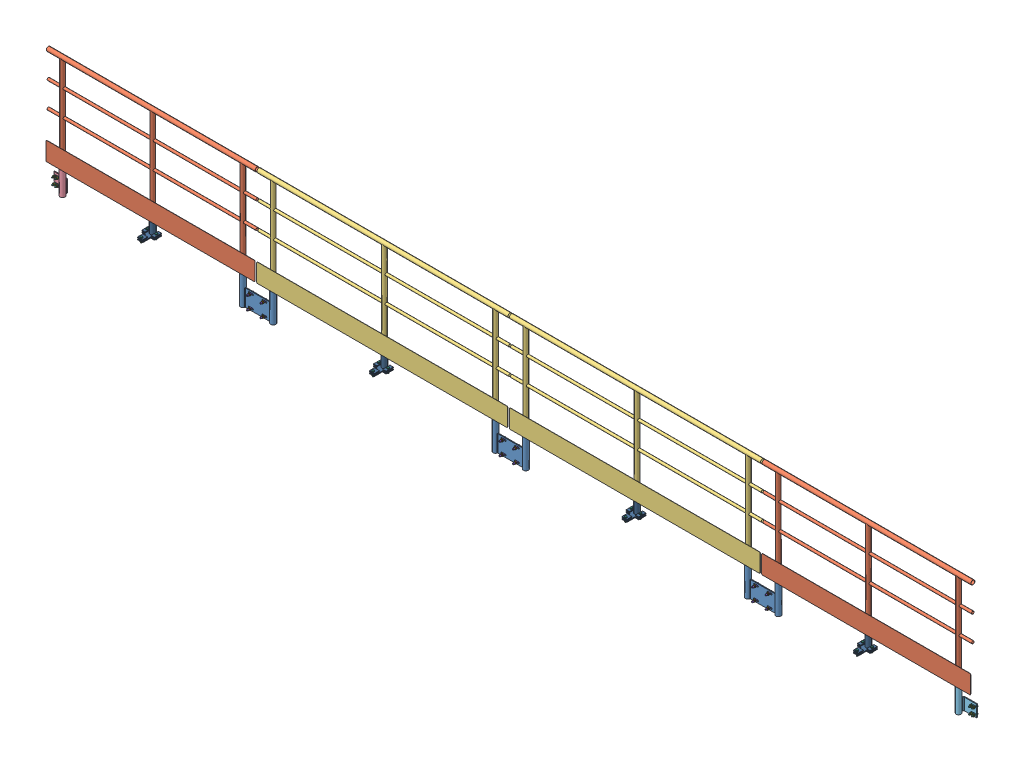
SolidWorks assembly 0402-RAILING ASSEMBLAGE, configuration Predeterminado. Lengths in mm.
Overall size (10980 1510 225).
76 component instances, 10 part files, 77 mates.
Components (placement in the parent):
- 0416-RAILING SUPPORT-1: 0416-RAILING SUPPORT [Predeterminado<Como mecanizada>] at (-587.6244 -491.8214 0) size (420 340 60)
- 0417-RAILING-1: 0417-RAILING [Predeterminado<Como mecanizada>] at (-3078.6244 -351.8214 -5) x (0 0 -1) z (1 0 0) size (53 1270 2480)
- 0420-LONG RAILING-1: 0420-LONG RAILING [Predeterminado<Como mecanizada>] at (-576.6244 -351.8214 -5) x (0 0 -1) z (1 0 0) size (53 1270 2980)
- 0416-RAILING SUPPORT-2: 0416-RAILING SUPPORT [Predeterminado<Como mecanizada>] at (2412.3756 -491.8214 0) size (420 340 60)
- 0416-RAILING SUPPORT-3: 0416-RAILING SUPPORT [Predeterminado<Como mecanizada>] at (5412.3756 -491.8214 0) size (420 340 60)
- 0420-LONG RAILING-2: 0420-LONG RAILING [Predeterminado<Como mecanizada>] at (2423.3756 -351.8214 -5) x (0 0 -1) z (1 0 0) size (53 1270 2980)
- 0417-RAILING-2: 0417-RAILING [Predeterminado<Como mecanizada>] at (5421.3756 -351.8214 -5) x (0 0 -1) z (1 0 0) size (53 1270 2480)
- 0421-RAILING SUPPORT-1: 0421-RAILING SUPPORT [Predeterminado<Como mecanizada>] at (-2909.6244 -531.8214 -5) x (0 0 -1) z (0 -1 0) size (96 190 280)
- 0422-RAILING SUPPORT-1: 0422-RAILING SUPPORT [Predeterminado<Como mecanizada>] at (7732.3756 -531.8214 -5) x (0 0 -1) z (0 -1 0) size (94 189 280)
- M-12x55 DIN-6914-18 and DIN-6916-1: M-12x55 DIN-6914-18 and DIN-6916 [DIN 6914 - M12 x 35 x 21-N] at (7876.3756 -422.8214 -80) x (0 0 1) z (-1 0 0) size (63 26 26)
- M-12x55 DIN-6914-18 and DIN-6916-2: M-12x55 DIN-6914-18 and DIN-6916 [DIN 6914 - M12 x 35 x 21-N] at (7841.3756 -422.8214 -80) x (0 0 1) z (-1 0 0) size (63 26 26)
- M-12x55 DIN-6914-18 and DIN-6916-3: M-12x55 DIN-6914-18 and DIN-6916 [DIN 6914 - M12 x 35 x 21-N] at (7876.3756 -502.8214 -80) x (0 0 1) z (-1 0 0) size (63 26 26)
- M-12x55 DIN-6914-18 and DIN-6916-6: M-12x55 DIN-6914-18 and DIN-6916 [DIN 6914 - M12 x 35 x 21-N] at (7841.3756 -502.8214 -80) x (0 0 1) z (-1 0 0) size (63 26 26)
- M-12 DIN-6915 and DIN-6916-2: M-12 DIN-6915 and DIN-6916 [Hexagon Nut DIN 6915 - M12 - N] at (7876.3756 -422.8214 -43) x (1 0 0) z (0 0 -1) size (26 26 12)
- M-12 DIN-6915 and DIN-6916-3: M-12 DIN-6915 and DIN-6916 [Hexagon Nut DIN 6915 - M12 - N] at (7841.3756 -422.8214 -43) x (1 0 0) z (0 0 -1) size (26 26 12)
- M-12 DIN-6915 and DIN-6916-4: M-12 DIN-6915 and DIN-6916 [Hexagon Nut DIN 6915 - M12 - N] at (7841.3756 -502.8214 -43) x (1 0 0) z (0 0 -1) size (26 26 12)
- M-12 DIN-6915 and DIN-6916-5: M-12 DIN-6915 and DIN-6916 [Hexagon Nut DIN 6915 - M12 - N] at (7876.3756 -502.8214 -43) x (1 0 0) z (0 0 -1) size (26 26 12)
- M-16x60 DIN-6914-18 and DIN-6916-1: M-16x60 DIN-6914-18 and DIN-6916 [DIN 6914 - M20 x 65 x 31-N] at (-668.1244 -415.8214 -26) x (0 0 1) z (0.5 0.866025 0) size (73 30 30)
- M-16x60 DIN-6914-18 and DIN-6916-7: M-16x60 DIN-6914-18 and DIN-6916 [DIN 6914 - M20 x 65 x 31-N] at (-668.1244 -565.8214 -26) x (0 0 1) z (0.5 0.866025 0) size (73 30 30)
- M-16 DIN-6915 and DIN-6916-1: M-16 DIN-6915 and DIN-6916 [Hexagon Nut DIN 6915 - M20 - N] at (-668.1244 -415.8214 18) x (-0.923728 -0.383049 0) z (0 0 -1) size (30 30 16)
- M-16 DIN-6915 and DIN-6916-2: M-16 DIN-6915 and DIN-6916 [Hexagon Nut DIN 6915 - M20 - N] at (-668.1244 -565.8214 18) x (-0.923728 -0.383049 0) z (0 0 -1) size (30 30 16)
- M-16 DIN-6915 and DIN-6916-5: M-16 DIN-6915 and DIN-6916 [Hexagon Nut DIN 6915 - M20 - N] at (-508.1244 -565.8214 18) x (-0.923728 -0.383049 0) z (0 0 -1) size (30 30 16)
- M-16x60 DIN-6914-18 and DIN-6916-10: M-16x60 DIN-6914-18 and DIN-6916 [DIN 6914 - M20 x 65 x 31-N] at (-508.1244 -565.8214 -26) x (0 0 1) z (0.5 0.866025 0) size (73 30 30)
- M-16 DIN-6915 and DIN-6916-6: M-16 DIN-6915 and DIN-6916 [Hexagon Nut DIN 6915 - M20 - N] at (-508.1244 -415.8214 18) x (-0.923728 -0.383049 0) z (0 0 -1) size (30 30 16)
- M-16x60 DIN-6914-18 and DIN-6916-11: M-16x60 DIN-6914-18 and DIN-6916 [DIN 6914 - M20 x 65 x 31-N] at (-508.1244 -415.8214 -26) x (0 0 1) z (0.5 0.866025 0) size (73 30 30)
- M-16 DIN-6915 and DIN-6916-7: M-16 DIN-6915 and DIN-6916 [Hexagon Nut DIN 6915 - M20 - N] at (2331.8756 -565.8214 18) x (-0.923728 -0.383049 0) z (0 0 -1) size (30 30 16)
- M-16 DIN-6915 and DIN-6916-8: M-16 DIN-6915 and DIN-6916 [Hexagon Nut DIN 6915 - M20 - N] at (5331.8756 -565.8214 18) x (-0.923728 -0.383049 0) z (0 0 -1) size (30 30 16)
- M-16 DIN-6915 and DIN-6916-9: M-16 DIN-6915 and DIN-6916 [Hexagon Nut DIN 6915 - M20 - N] at (2491.8756 -565.8214 18) x (-0.923728 -0.383049 0) z (0 0 -1) size (30 30 16)
- M-16 DIN-6915 and DIN-6916-10: M-16 DIN-6915 and DIN-6916 [Hexagon Nut DIN 6915 - M20 - N] at (5491.8756 -565.8214 18) x (-0.923728 -0.383049 0) z (0 0 -1) size (30 30 16)
- M-16 DIN-6915 and DIN-6916-11: M-16 DIN-6915 and DIN-6916 [Hexagon Nut DIN 6915 - M20 - N] at (2491.8756 -415.8214 18) x (-0.923728 -0.383049 0) z (0 0 -1) size (30 30 16)
- M-16 DIN-6915 and DIN-6916-12: M-16 DIN-6915 and DIN-6916 [Hexagon Nut DIN 6915 - M20 - N] at (5491.8756 -415.8214 18) x (-0.923728 -0.383049 0) z (0 0 -1) size (30 30 16)
- M-16 DIN-6915 and DIN-6916-13: M-16 DIN-6915 and DIN-6916 [Hexagon Nut DIN 6915 - M20 - N] at (2331.8756 -415.8214 18) x (-0.923728 -0.383049 0) z (0 0 -1) size (30 30 16)
- M-16 DIN-6915 and DIN-6916-14: M-16 DIN-6915 and DIN-6916 [Hexagon Nut DIN 6915 - M20 - N] at (5331.8756 -415.8214 18) x (-0.923728 -0.383049 0) z (0 0 -1) size (30 30 16)
- M-16x60 DIN-6914-18 and DIN-6916-12: M-16x60 DIN-6914-18 and DIN-6916 [DIN 6914 - M20 x 65 x 31-N] at (2331.8756 -565.8214 -26) x (0 0 1) z (0.5 0.866025 0) size (73 30 30)
- M-16x60 DIN-6914-18 and DIN-6916-13: M-16x60 DIN-6914-18 and DIN-6916 [DIN 6914 - M20 x 65 x 31-N] at (5331.8756 -565.8214 -26) x (0 0 1) z (0.5 0.866025 0) size (73 30 30)
- M-16x60 DIN-6914-18 and DIN-6916-14: M-16x60 DIN-6914-18 and DIN-6916 [DIN 6914 - M20 x 65 x 31-N] at (2491.8756 -565.8214 -26) x (0 0 1) z (0.5 0.866025 0) size (73 30 30)
- M-16x60 DIN-6914-18 and DIN-6916-15: M-16x60 DIN-6914-18 and DIN-6916 [DIN 6914 - M20 x 65 x 31-N] at (5491.8756 -565.8214 -26) x (0 0 1) z (0.5 0.866025 0) size (73 30 30)
- M-16x60 DIN-6914-18 and DIN-6916-16: M-16x60 DIN-6914-18 and DIN-6916 [DIN 6914 - M20 x 65 x 31-N] at (2331.8756 -415.8214 -26) x (0 0 1) z (0.5 0.866025 0) size (73 30 30)
- M-16x60 DIN-6914-18 and DIN-6916-17: M-16x60 DIN-6914-18 and DIN-6916 [DIN 6914 - M20 x 65 x 31-N] at (5331.8756 -415.8214 -26) x (0 0 1) z (0.5 0.866025 0) size (73 30 30)
- M-16x60 DIN-6914-18 and DIN-6916-18: M-16x60 DIN-6914-18 and DIN-6916 [DIN 6914 - M20 x 65 x 31-N] at (2491.8756 -415.8214 -26) x (0 0 1) z (0.5 0.866025 0) size (73 30 30)
- M-16x60 DIN-6914-18 and DIN-6916-19: M-16x60 DIN-6914-18 and DIN-6916 [DIN 6914 - M20 x 65 x 31-N] at (5491.8756 -415.8214 -26) x (0 0 1) z (0.5 0.866025 0) size (73 30 30)
- M-12x55 DIN-6914-18 and DIN-6916-7: M-12x55 DIN-6914-18 and DIN-6916 [DIN 6914 - M12 x 35 x 21-N] at (-3013.6244 -502.8214 -80) x (0 0 1) z (-1 0 0) size (63 26 26)
- M-12 DIN-6915 and DIN-6916-6: M-12 DIN-6915 and DIN-6916 [Hexagon Nut DIN 6915 - M12 - N] at (-3013.6244 -502.8214 -43) x (1 0 0) z (0 0 -1) size (26 26 12)
- M-12 DIN-6915 and DIN-6916-7: M-12 DIN-6915 and DIN-6916 [Hexagon Nut DIN 6915 - M12 - N] at (-3048.6244 -502.8214 -43) x (1 0 0) z (0 0 -1) size (26 26 12)
- M-12x55 DIN-6914-18 and DIN-6916-8: M-12x55 DIN-6914-18 and DIN-6916 [DIN 6914 - M12 x 35 x 21-N] at (-3048.6244 -502.8214 -80) x (0 0 1) z (-1 0 0) size (63 26 26)
- M-12 DIN-6915 and DIN-6916-8: M-12 DIN-6915 and DIN-6916 [Hexagon Nut DIN 6915 - M12 - N] at (-3013.6244 -422.8214 -43) x (1 0 0) z (0 0 -1) size (26 26 12)
- M-12x55 DIN-6914-18 and DIN-6916-9: M-12x55 DIN-6914-18 and DIN-6916 [DIN 6914 - M12 x 35 x 21-N] at (-3013.6244 -422.8214 -80) x (0 0 1) z (-1 0 0) size (63 26 26)
- M-12 DIN-6915 and DIN-6916-9: M-12 DIN-6915 and DIN-6916 [Hexagon Nut DIN 6915 - M12 - N] at (-3048.6244 -422.8214 -43) x (1 0 0) z (0 0 -1) size (26 26 12)
- M-12x55 DIN-6914-18 and DIN-6916-10: M-12x55 DIN-6914-18 and DIN-6916 [DIN 6914 - M12 x 35 x 21-N] at (-3048.6244 -422.8214 -80) x (0 0 1) z (-1 0 0) size (63 26 26)
- 0423-RAILING SUPPORT-1: 0423-RAILING SUPPORT [Predeterminado<Como mecanizada>] at (-1838.6244 -381.8214 -5) x (1 0 0) z (0 -1 0) size (150 180 140)
- M-12x55 DIN-6914-18 and DIN-6916-11: M-12x55 DIN-6914-18 and DIN-6916 [DIN 6914 - M12 x 35 x 21-N] at (-1893.6244 -351.8214 7.5) x (0 -1 0) z (0 0 1) size (63 26 26)
- M-12x55 DIN-6914-18 and DIN-6916-12: M-12x55 DIN-6914-18 and DIN-6916 [DIN 6914 - M12 x 35 x 21-N] at (-1783.6244 -351.8214 7.5) x (0 -1 0) z (0 0 1) size (63 26 26)
- M-12x55 DIN-6914-18 and DIN-6916-13: M-12x55 DIN-6914-18 and DIN-6916 [DIN 6914 - M12 x 35 x 21-N] at (-1838.6244 -351.8214 130) x (0 -1 0) z (0 0 1) size (63 26 26)
- M-12 DIN-6915 and DIN-6916-10: M-12 DIN-6915 and DIN-6916 [Hexagon Nut DIN 6915 - M12 - N] at (-1893.6244 -393.8214 7.5) x (1 0 0) z (0 1 0) size (26 26 12)
- M-12 DIN-6915 and DIN-6916-11: M-12 DIN-6915 and DIN-6916 [Hexagon Nut DIN 6915 - M12 - N] at (-1783.6244 -393.8214 7.5) x (1 0 0) z (0 1 0) size (26 26 12)
- M-12 DIN-6915 and DIN-6916-12: M-12 DIN-6915 and DIN-6916 [Hexagon Nut DIN 6915 - M12 - N] at (-1838.6244 -393.8214 130) x (1 0 0) z (0 1 0) size (26 26 12)
- M-12x55 DIN-6914-18 and DIN-6916-14: M-12x55 DIN-6914-18 and DIN-6916 [DIN 6914 - M12 x 35 x 21-N] at (6661.3756 -351.8214 130) x (0 -1 0) z (0 0 1) size (63 26 26)
- M-12x55 DIN-6914-18 and DIN-6916-15: M-12x55 DIN-6914-18 and DIN-6916 [DIN 6914 - M12 x 35 x 21-N] at (6606.3756 -351.8214 7.5) x (0 -1 0) z (0 0 1) size (63 26 26)
- M-12 DIN-6915 and DIN-6916-13: M-12 DIN-6915 and DIN-6916 [Hexagon Nut DIN 6915 - M12 - N] at (6606.3756 -393.8214 7.5) x (1 0 0) z (0 1 0) size (26 26 12)
- M-12 DIN-6915 and DIN-6916-14: M-12 DIN-6915 and DIN-6916 [Hexagon Nut DIN 6915 - M12 - N] at (6716.3756 -393.8214 7.5) x (1 0 0) z (0 1 0) size (26 26 12)
- M-12x55 DIN-6914-18 and DIN-6916-16: M-12x55 DIN-6914-18 and DIN-6916 [DIN 6914 - M12 x 35 x 21-N] at (6716.3756 -351.8214 7.5) x (0 -1 0) z (0 0 1) size (63 26 26)
- 0423-RAILING SUPPORT-2: 0423-RAILING SUPPORT [Predeterminado<Como mecanizada>] at (6661.3756 -381.8214 -5) x (1 0 0) z (0 -1 0) size (150 180 140)
- 0423-RAILING SUPPORT-3: 0423-RAILING SUPPORT [Predeterminado<Como mecanizada>] at (913.3756 -381.8214 -5) x (1 0 0) z (0 -1 0) size (150 180 140)
- M-12x55 DIN-6914-18 and DIN-6916-17: M-12x55 DIN-6914-18 and DIN-6916 [DIN 6914 - M12 x 35 x 21-N] at (858.3756 -351.8214 7.5) x (0 -1 0) z (0 0 1) size (63 26 26)
- M-12x55 DIN-6914-18 and DIN-6916-18: M-12x55 DIN-6914-18 and DIN-6916 [DIN 6914 - M12 x 35 x 21-N] at (968.3756 -351.8214 7.5) x (0 -1 0) z (0 0 1) size (63 26 26)
- M-12x55 DIN-6914-18 and DIN-6916-19: M-12x55 DIN-6914-18 and DIN-6916 [DIN 6914 - M12 x 35 x 21-N] at (913.3756 -351.8214 130) x (0 -1 0) z (0 0 1) size (63 26 26)
- M-12 DIN-6915 and DIN-6916-15: M-12 DIN-6915 and DIN-6916 [Hexagon Nut DIN 6915 - M12 - N] at (858.3756 -393.8214 7.5) x (1 0 0) z (0 1 0) size (26 26 12)
- M-12 DIN-6915 and DIN-6916-16: M-12 DIN-6915 and DIN-6916 [Hexagon Nut DIN 6915 - M12 - N] at (968.3756 -393.8214 7.5) x (1 0 0) z (0 1 0) size (26 26 12)
- M-12 DIN-6915 and DIN-6916-17: M-12 DIN-6915 and DIN-6916 [Hexagon Nut DIN 6915 - M12 - N] at (913.3756 -393.8214 130) x (1 0 0) z (0 1 0) size (26 26 12)
- M-12 DIN-6915 and DIN-6916-18: M-12 DIN-6915 and DIN-6916 [Hexagon Nut DIN 6915 - M12 - N] at (3913.3756 -393.8214 130) x (1 0 0) z (0 1 0) size (26 26 12)
- M-12x55 DIN-6914-18 and DIN-6916-20: M-12x55 DIN-6914-18 and DIN-6916 [DIN 6914 - M12 x 35 x 21-N] at (3913.3756 -351.8214 130) x (0 -1 0) z (0 0 1) size (63 26 26)
- M-12x55 DIN-6914-18 and DIN-6916-21: M-12x55 DIN-6914-18 and DIN-6916 [DIN 6914 - M12 x 35 x 21-N] at (3858.3756 -351.8214 7.5) x (0 -1 0) z (0 0 1) size (63 26 26)
- M-12 DIN-6915 and DIN-6916-19: M-12 DIN-6915 and DIN-6916 [Hexagon Nut DIN 6915 - M12 - N] at (3858.3756 -393.8214 7.5) x (1 0 0) z (0 1 0) size (26 26 12)
- M-12 DIN-6915 and DIN-6916-20: M-12 DIN-6915 and DIN-6916 [Hexagon Nut DIN 6915 - M12 - N] at (3968.3756 -393.8214 7.5) x (1 0 0) z (0 1 0) size (26 26 12)
- M-12x55 DIN-6914-18 and DIN-6916-22: M-12x55 DIN-6914-18 and DIN-6916 [DIN 6914 - M12 x 35 x 21-N] at (3968.3756 -351.8214 7.5) x (0 -1 0) z (0 0 1) size (63 26 26)
- 0423-RAILING SUPPORT-4: 0423-RAILING SUPPORT [Predeterminado<Como mecanizada>] at (3913.3756 -381.8214 -5) x (1 0 0) z (0 -1 0) size (150 180 140)
Mates (geometry in assembly coordinates):
- Concéntrica1: concentric anti-aligned: cylinder of 0417-RAILING-1 through (-767.6244 918.1796 -5) axis (0 -1 0) radius 25; cylinder of 0416-RAILING SUPPORT-1 through (-767.6244 -251.8214 -5) axis (0 1 0) radius 26
- Coincidente7: coincident anti-aligned: plane of 0417-RAILING-1 through (-598.6244 -251.8214 23) normal (0 -1 0); plane of 0416-RAILING SUPPORT-1 through (-767.6244 -251.8214 -5) normal (0 1 0)
- Paralelo1: parallel anti-aligned: plane of 0416-RAILING SUPPORT-1 through (-737.6244 -591.8214 -10) normal (-1 0 0); plane of 0417-RAILING-1 through (-598.6244 -31.8214 23) normal (1 0 0)
- Concéntrica2: concentric anti-aligned: cylinder of 0420-LONG RAILING-1 through (-407.6244 918.1796 -5) axis (0 -1 0) radius 25; cylinder of 0416-RAILING SUPPORT-1 through (-407.6244 -251.8214 -5) axis (0 1 0) radius 26
- Coincidente16: coincident anti-aligned: plane of 0416-RAILING SUPPORT-1 through (-407.6244 -251.8214 -5) normal (0 1 0); plane of 0420-LONG RAILING-1 through (2403.3756 -251.8214 23) normal (0 -1 0)
- Concéntrica3: concentric aligned: cylinder of 0417-RAILING-1 through (-2909.6244 918.1796 -5) axis (0 -1 0) radius 25; cylinder of 0421-RAILING SUPPORT-1 through (-2909.6244 -251.8214 -5) axis (0 -1 0) radius 26
- Coincidente17: coincident anti-aligned: plane of 0417-RAILING-1 through (-598.6244 -251.8214 23) normal (0 -1 0); plane of 0421-RAILING SUPPORT-1 through (-2909.6244 -251.8214 -5) normal (0 1 0)
- Paralelo2: parallel aligned: plane of 0417-RAILING-1 through (-3078.6244 -31.8214 23) normal (-1 0 0); plane of 0421-RAILING SUPPORT-1 through (-2914.6244 -391.8214 -35) normal (-1 0 0)
- Concéntrica4: concentric aligned: cylinder of 0417-RAILING-2 through (7732.3756 918.1796 -5) axis (0 -1 0) radius 22; cylinder of 0422-RAILING SUPPORT-1 through (7732.3756 -251.8214 -5) axis (0 -1 0) radius 29
- Coincidente18: coincident anti-aligned: plane of 0417-RAILING-2 through (7901.3756 -251.8214 23) normal (0 -1 0); plane of 0422-RAILING SUPPORT-1 through (7732.3756 -251.8214 -5) normal (0 1 0)
- Paralelo3: parallel aligned: plane of 0417-RAILING-2 through (7901.3756 -31.8214 23) normal (1 0 0); plane of 0422-RAILING SUPPORT-1 through (7737.3756 -391.8214 -50) normal (1 0 0)
- Tangente5: tangent anti-aligned: plane of 0422-RAILING SUPPORT-1 through (7892.3756 -428.8214 8.4471) normal (0 1 0); cylinder of M-12x55 DIN-6914-18 and DIN-6916-1 through (7876.3756 -422.8214 -80) axis (0 0 -1) radius 6
- Coincidente28: coincident anti-aligned: plane of 0422-RAILING SUPPORT-1 through (7892.3756 -391.8214 -70) normal (0 0 -1); plane of M-12x55 DIN-6914-18 and DIN-6916-1 through (7876.3756 -422.8214 -70) normal (0 0 1)
- Distancia12: distance = 5 mm aligned: plane of M-12x55 DIN-6914-18 and DIN-6916-1 through (7887.3756 -416.4705 -72) normal (1 0 0); plane of 0422-RAILING SUPPORT-1 through (7892.3756 -391.8214 -60) normal (1 0 0)
- Tangente6: tangent anti-aligned: plane of 0422-RAILING SUPPORT-1 through (7892.3756 -428.8214 8.4471) normal (0 1 0); cylinder of M-12x55 DIN-6914-18 and DIN-6916-2 through (7841.3756 -422.8214 -80) axis (0 0 -1) radius 6
- Coincidente30: coincident anti-aligned: plane of 0422-RAILING SUPPORT-1 through (7892.3756 -391.8214 -70) normal (0 0 -1); plane of M-12x55 DIN-6914-18 and DIN-6916-2 through (7841.3756 -422.8214 -70) normal (0 0 1)
- Distancia13: distance = 40 mm aligned: plane of M-12x55 DIN-6914-18 and DIN-6916-2 through (7852.3756 -416.4705 -72) normal (1 0 0); plane of 0422-RAILING SUPPORT-1 through (7892.3756 -391.8214 -60) normal (1 0 0)
- Tangente7: tangent anti-aligned: cylinder of M-12x55 DIN-6914-18 and DIN-6916-3 through (7876.3756 -502.8214 -80) axis (0 0 -1) radius 6; plane of 0422-RAILING SUPPORT-1 through (7892.3756 -508.8214 8.4471) normal (0 1 0)
- Coincidente31: coincident anti-aligned: plane of 0422-RAILING SUPPORT-1 through (7892.3756 -391.8214 -70) normal (0 0 -1); plane of M-12x55 DIN-6914-18 and DIN-6916-3 through (7876.3756 -502.8214 -70) normal (0 0 1)
- Distancia16: distance = 5 mm aligned: plane of M-12x55 DIN-6914-18 and DIN-6916-3 through (7887.3756 -496.4705 -72) normal (1 0 0); plane of 0422-RAILING SUPPORT-1 through (7892.3756 -391.8214 -60) normal (1 0 0)
- Tangente8: tangent anti-aligned: plane of 0422-RAILING SUPPORT-1 through (7892.3756 -508.8214 8.4471) normal (0 1 0); cylinder of M-12x55 DIN-6914-18 and DIN-6916-6 through (7841.3756 -502.8214 -80) axis (0 0 -1) radius 6
- Coincidente33: coincident anti-aligned: plane of 0422-RAILING SUPPORT-1 through (7892.3756 -391.8214 -70) normal (0 0 -1); plane of M-12x55 DIN-6914-18 and DIN-6916-6 through (7841.3756 -502.8214 -70) normal (0 0 1)
- Distancia20: distance = 40 mm aligned: plane of M-12x55 DIN-6914-18 and DIN-6916-6 through (7852.3756 -496.4705 -72) normal (1 0 0); plane of 0422-RAILING SUPPORT-1 through (7892.3756 -391.8214 -60) normal (1 0 0)
- Distancia23: distance = 15 mm anti-aligned: plane of M-12 DIN-6915 and DIN-6916-2 through (7876.3756 -422.8214 -45) normal (0 0 -1); plane of 0422-RAILING SUPPORT-1 through (7747.3756 -391.8214 -60) normal (0 0 1)
- Concéntrica6: concentric aligned: cylinder of M-12x55 DIN-6914-18 and DIN-6916-1 through (7876.3756 -422.8214 -80) axis (0 0 -1) radius 6; cylinder of M-12 DIN-6915 and DIN-6916-2 through (7876.3756 -422.8214 -33) axis (0 0 -1) radius 5.1
- Distancia24: distance = 15 mm anti-aligned: plane of M-12 DIN-6915 and DIN-6916-3 through (7841.3756 -422.8214 -45) normal (0 0 -1); plane of 0422-RAILING SUPPORT-1 through (7747.3756 -391.8214 -60) normal (0 0 1)
- Concéntrica7: concentric aligned: cylinder of M-12x55 DIN-6914-18 and DIN-6916-2 through (7841.3756 -422.8214 -80) axis (0 0 -1) radius 6; cylinder of M-12 DIN-6915 and DIN-6916-3 through (7841.3756 -422.8214 -33) axis (0 0 -1) radius 5.1
- Distancia25: distance = 15 mm anti-aligned: plane of M-12 DIN-6915 and DIN-6916-4 through (7841.3756 -502.8214 -45) normal (0 0 -1); plane of 0422-RAILING SUPPORT-1 through (7747.3756 -391.8214 -60) normal (0 0 1)
- Concéntrica8: concentric aligned: cylinder of M-12x55 DIN-6914-18 and DIN-6916-6 through (7841.3756 -502.8214 -80) axis (0 0 -1) radius 6; cylinder of M-12 DIN-6915 and DIN-6916-4 through (7841.3756 -502.8214 -33) axis (0 0 -1) radius 5.1
- Distancia26: distance = 15 mm anti-aligned: plane of M-12 DIN-6915 and DIN-6916-5 through (7876.3756 -502.8214 -45) normal (0 0 -1); plane of 0422-RAILING SUPPORT-1 through (7747.3756 -391.8214 -60) normal (0 0 1)
- Concéntrica9: concentric aligned: cylinder of M-12x55 DIN-6914-18 and DIN-6916-3 through (7876.3756 -502.8214 -80) axis (0 0 -1) radius 6; cylinder of M-12 DIN-6915 and DIN-6916-5 through (7876.3756 -502.8214 -33) axis (0 0 -1) radius 5.1
- Coincidente37: coincident anti-aligned: plane of 0416-RAILING SUPPORT-1 through (-437.6244 -591.8214 -10) normal (0 0 -1); plane of M-16x60 DIN-6914-18 and DIN-6916-1 through (-668.1244 -415.8214 -10) normal (0 0 1)
- Tangente10: tangent anti-aligned: cylinder of M-16x60 DIN-6914-18 and DIN-6916-1 through (-668.1244 -415.8214 -26) axis (0 0 -1) radius 8; plane of 0416-RAILING SUPPORT-1 through (-647.6244 -407.8214 -10) normal (0 -1 0)
- Distancia28: distance = 57.5 mm aligned: plane of M-16x60 DIN-6914-18 and DIN-6916-1 through (-680.1244 -422.7496 -13) normal (-1 0 0); plane of 0416-RAILING SUPPORT-1 through (-737.6244 -591.8214 -10) normal (-1 0 0)
- Coincidente43: coincident anti-aligned: plane of 0416-RAILING SUPPORT-1 through (-437.6244 -591.8214 -10) normal (0 0 -1); plane of M-16x60 DIN-6914-18 and DIN-6916-7 through (-668.1244 -565.8214 -10) normal (0 0 1)
- Tangente12: tangent anti-aligned: cylinder of M-16x60 DIN-6914-18 and DIN-6916-7 through (-668.1244 -565.8214 -26) axis (0 0 -1) radius 8; plane of 0416-RAILING SUPPORT-1 through (-647.6244 -557.8214 -10) normal (0 -1 0)
- Distancia31: distance = 57.5 mm aligned: plane of M-16x60 DIN-6914-18 and DIN-6916-7 through (-680.1244 -572.7496 -13) normal (-1 0 0); plane of 0416-RAILING SUPPORT-1 through (-737.6244 -591.8214 -10) normal (-1 0 0)
- Distancia32: distance = 15 mm anti-aligned: plane of M-16 DIN-6915 and DIN-6916-1 through (-668.1244 -415.8214 15) normal (0 0 -1); plane of 0416-RAILING SUPPORT-1 through (-437.6244 -591.8214 0) normal (0 0 1)
- Concéntrica10: concentric aligned: cylinder of M-16x60 DIN-6914-18 and DIN-6916-1 through (-668.1244 -415.8214 -26) axis (0 0 -1) radius 8; cylinder of M-16 DIN-6915 and DIN-6916-1 through (-668.1244 -415.8214 31) axis (0 0 -1) radius 8
- Distancia33: distance = 15 mm anti-aligned: plane of M-16 DIN-6915 and DIN-6916-2 through (-668.1244 -565.8214 15) normal (0 0 -1); plane of 0416-RAILING SUPPORT-1 through (-437.6244 -591.8214 0) normal (0 0 1)
- Concéntrica11: concentric aligned: cylinder of M-16x60 DIN-6914-18 and DIN-6916-7 through (-668.1244 -565.8214 -26) axis (0 0 -1) radius 8; cylinder of M-16 DIN-6915 and DIN-6916-2 through (-668.1244 -565.8214 31) axis (0 0 -1) radius 8
- Concéntrica12: concentric aligned: cylinder of 0417-RAILING-1 through (-1838.6244 918.1796 -5) axis (0 -1 0) radius 25; cylinder of 0423-RAILING SUPPORT-1 through (-1838.6244 -251.8214 -5) axis (0 -1 0) radius 26
- Paralelo4: parallel aligned: plane of 0417-RAILING-1 through (-598.6244 -251.8214 20) normal (0 0 -1); plane of 0423-RAILING SUPPORT-1 through (-1913.6244 -391.8214 -35) normal (0 0 -1)
- Distancia34: distance = 30 mm anti-aligned: plane of 0423-RAILING SUPPORT-1 through (-1913.6244 -381.8214 50) normal (0 1 0); plane of 0417-RAILING-1 through (-1838.6244 -351.8214 -5) normal (0 -1 0)
- Coincidente46: coincident anti-aligned: plane of 0423-RAILING SUPPORT-1 through (-1913.6244 -361.8214 -35) normal (0 1 0); plane of M-12x55 DIN-6914-18 and DIN-6916-11 through (-1893.6244 -361.8214 7.5) normal (0 -1 0)
- Concéntrica13: concentric anti-aligned: cylinder of 0423-RAILING SUPPORT-1 through (-1893.6244 -361.8214 7.5) axis (0 -1 0) radius 7; cylinder of M-12x55 DIN-6914-18 and DIN-6916-11 through (-1893.6244 -351.8214 7.5) axis (0 1 0) radius 6
- Coincidente47: coincident anti-aligned: plane of 0423-RAILING SUPPORT-1 through (-1913.6244 -361.8214 -35) normal (0 1 0); plane of M-12x55 DIN-6914-18 and DIN-6916-12 through (-1783.6244 -361.8214 7.5) normal (0 -1 0)
- Concéntrica14: concentric anti-aligned: cylinder of 0423-RAILING SUPPORT-1 through (-1783.6244 -361.8214 7.5) axis (0 -1 0) radius 7; cylinder of M-12x55 DIN-6914-18 and DIN-6916-12 through (-1783.6244 -351.8214 7.5) axis (0 1 0) radius 6
- Coincidente48: coincident anti-aligned: plane of 0423-RAILING SUPPORT-1 through (-1913.6244 -361.8214 -35) normal (0 1 0); plane of M-12x55 DIN-6914-18 and DIN-6916-13 through (-1838.6244 -361.8214 130) normal (0 -1 0)
- Concéntrica15: concentric anti-aligned: cylinder of 0423-RAILING SUPPORT-1 through (-1838.6244 -361.8214 130) axis (0 -1 0) radius 7; cylinder of M-12x55 DIN-6914-18 and DIN-6916-13 through (-1838.6244 -351.8214 130) axis (0 1 0) radius 6
- Coincidente49: coincident anti-aligned: plane of 0423-RAILING SUPPORT-1 through (-1913.6244 -391.8214 50) normal (0 -1 0); plane of M-12 DIN-6915 and DIN-6916-10 through (-1893.6244 -391.8214 7.5) normal (0 1 0)
- Concéntrica16: concentric aligned: cylinder of M-12x55 DIN-6914-18 and DIN-6916-11 through (-1893.6244 -351.8214 7.5) axis (0 1 0) radius 6; cylinder of M-12 DIN-6915 and DIN-6916-10 through (-1893.6244 -403.8214 7.5) axis (0 1 0) radius 5.1
- Coincidente50: coincident anti-aligned: plane of 0423-RAILING SUPPORT-1 through (-1913.6244 -391.8214 50) normal (0 -1 0); plane of M-12 DIN-6915 and DIN-6916-11 through (-1783.6244 -391.8214 7.5) normal (0 1 0)
- Concéntrica17: concentric aligned: cylinder of M-12x55 DIN-6914-18 and DIN-6916-12 through (-1783.6244 -351.8214 7.5) axis (0 1 0) radius 6; cylinder of M-12 DIN-6915 and DIN-6916-11 through (-1783.6244 -403.8214 7.5) axis (0 1 0) radius 5.1
- Coincidente51: coincident anti-aligned: plane of 0423-RAILING SUPPORT-1 through (-1913.6244 -391.8214 50) normal (0 -1 0); plane of M-12 DIN-6915 and DIN-6916-12 through (-1838.6244 -391.8214 130) normal (0 1 0)
- Concéntrica18: concentric aligned: cylinder of M-12x55 DIN-6914-18 and DIN-6916-13 through (-1838.6244 -351.8214 130) axis (0 1 0) radius 6; cylinder of M-12 DIN-6915 and DIN-6916-12 through (-1838.6244 -403.8214 130) axis (0 1 0) radius 5.1
- Concéntrica19: concentric aligned: cylinder of 0420-LONG RAILING-1 through (913.3756 918.1796 -5) axis (0 -1 0) radius 25; cylinder of 0423-RAILING SUPPORT-3 through (913.3756 -251.8214 -5) axis (0 -1 0) radius 26
- Coincidente52: coincident anti-aligned: plane of 0420-LONG RAILING-1 through (2403.3756 -251.8214 23) normal (0 -1 0); plane of 0423-RAILING SUPPORT-3 through (913.3756 -251.8214 -5) normal (0 1 0)
- Paralelo5: parallel aligned: plane of 0420-LONG RAILING-1 through (2403.3756 -251.8214 20) normal (0 0 -1); plane of 0423-RAILING SUPPORT-3 through (948.3756 -361.8214 -35) normal (0 0 -1)
- Concéntrica20: concentric anti-aligned: cylinder of 0423-RAILING SUPPORT-3 through (858.3756 -361.8214 7.5) axis (0 -1 0) radius 7; cylinder of M-12x55 DIN-6914-18 and DIN-6916-17 through (858.3756 -351.8214 7.5) axis (0 1 0) radius 6
- Coincidente55: coincident anti-aligned: plane of 0423-RAILING SUPPORT-3 through (838.3756 -361.8214 -35) normal (0 1 0); plane of M-12x55 DIN-6914-18 and DIN-6916-17 through (858.3756 -361.8214 7.5) normal (0 -1 0)
- Concéntrica21: concentric anti-aligned: cylinder of 0423-RAILING SUPPORT-3 through (968.3756 -361.8214 7.5) axis (0 -1 0) radius 7; cylinder of M-12x55 DIN-6914-18 and DIN-6916-18 through (968.3756 -351.8214 7.5) axis (0 1 0) radius 6
- Coincidente56: coincident anti-aligned: plane of 0423-RAILING SUPPORT-3 through (838.3756 -361.8214 -35) normal (0 1 0); plane of M-12x55 DIN-6914-18 and DIN-6916-18 through (968.3756 -361.8214 7.5) normal (0 -1 0)
- Concéntrica22: concentric anti-aligned: cylinder of 0423-RAILING SUPPORT-3 through (913.3756 -361.8214 130) axis (0 -1 0) radius 7; cylinder of M-12x55 DIN-6914-18 and DIN-6916-19 through (913.3756 -351.8214 130) axis (0 1 0) radius 6
- Coincidente57: coincident anti-aligned: plane of 0423-RAILING SUPPORT-3 through (838.3756 -361.8214 -35) normal (0 1 0); plane of M-12x55 DIN-6914-18 and DIN-6916-19 through (913.3756 -361.8214 130) normal (0 -1 0)
- Concéntrica23: concentric aligned: cylinder of M-12x55 DIN-6914-18 and DIN-6916-17 through (858.3756 -351.8214 7.5) axis (0 1 0) radius 6; cylinder of M-12 DIN-6915 and DIN-6916-15 through (858.3756 -403.8214 7.5) axis (0 1 0) radius 5.1
- Coincidente59: coincident anti-aligned: plane of 0423-RAILING SUPPORT-3 through (838.3756 -391.8214 50) normal (0 -1 0); plane of M-12 DIN-6915 and DIN-6916-15 through (858.3756 -391.8214 7.5) normal (0 1 0)
- Concéntrica24: concentric aligned: cylinder of M-12x55 DIN-6914-18 and DIN-6916-18 through (968.3756 -351.8214 7.5) axis (0 1 0) radius 6; cylinder of M-12 DIN-6915 and DIN-6916-16 through (968.3756 -403.8214 7.5) axis (0 1 0) radius 5.1
- Coincidente60: coincident anti-aligned: plane of 0423-RAILING SUPPORT-3 through (838.3756 -391.8214 50) normal (0 -1 0); plane of M-12 DIN-6915 and DIN-6916-16 through (968.3756 -391.8214 7.5) normal (0 1 0)
- Concéntrica25: concentric aligned: cylinder of M-12x55 DIN-6914-18 and DIN-6916-19 through (913.3756 -351.8214 130) axis (0 1 0) radius 6; cylinder of M-12 DIN-6915 and DIN-6916-17 through (913.3756 -403.8214 130) axis (0 1 0) radius 5.1
- Coincidente61: coincident anti-aligned: plane of 0423-RAILING SUPPORT-3 through (838.3756 -391.8214 50) normal (0 -1 0); plane of M-12 DIN-6915 and DIN-6916-17 through (913.3756 -391.8214 130) normal (0 1 0)
- MatrizL local1: unknown: line of 0416-RAILING SUPPORT-1 through (-437.6244 -591.8214 -10) axis (-1 0 0)
- MatrizL local2: unknown: line of 0416-RAILING SUPPORT-1 through (-437.6244 -591.8214 -10) axis (-1 0 0)
- MatrizL local3: unknown: line of 0416-RAILING SUPPORT-1 through (-437.6244 -591.8214 -10) axis (-1 0 0)
- MatrizL local4: unknown: line of 0416-RAILING SUPPORT-1 through (-737.6244 -391.8214 -10) axis (1 0 0)
- MatrizL local5: unknown: line of 0416-RAILING SUPPORT-1 through (-737.6244 -391.8214 -10) axis (1 0 0)
- MatrizL local8: unknown: line of 0422-RAILING SUPPORT-1 through (7747.3756 -391.8214 -70) axis (1 0 0)
